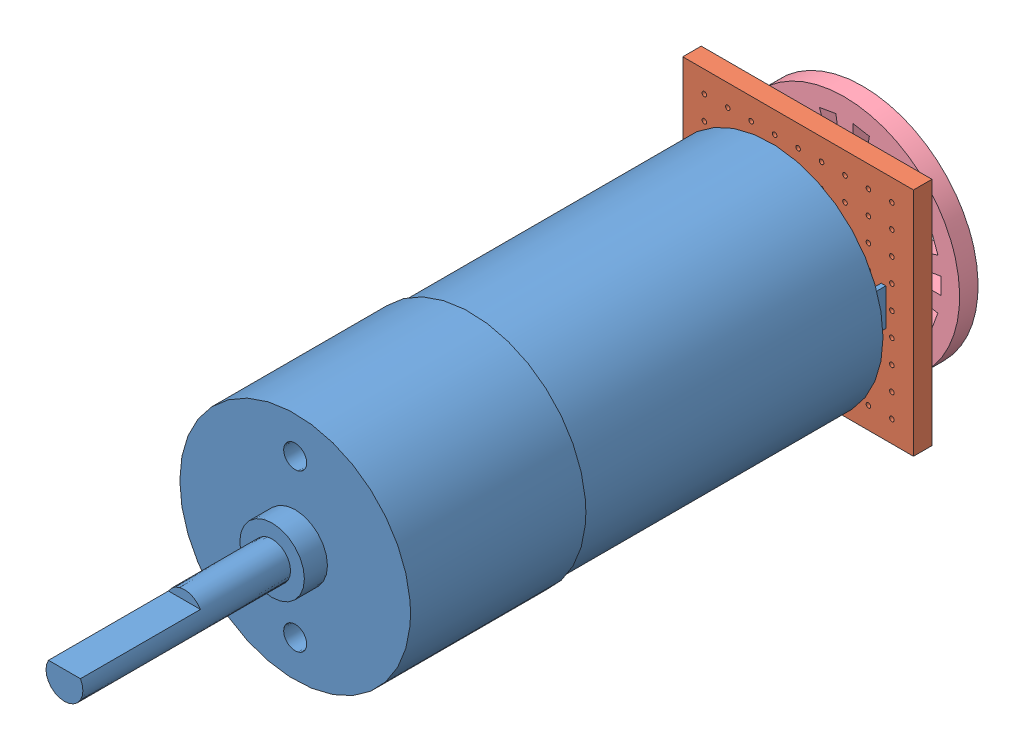
SolidWorks assembly motor_asm, configuration Default. Lengths in mm.
Overall size (31.79 31.79 86.5).
5 component instances, 4 part files, 11 mates.
Components (placement in the parent):
- DCMOTOR25 6v 325rpm-1: DCMOTOR25 6v 325rpm [Default] at (25.2687 40.3416 68.9723) size (25 25 84.5)
- encoder_pcb-1: encoder_pcb [Default] at (25.2687 40.3416 31.4723) x (1 0 0) z (0 -1 0) size (25 2 25)
- qre1113gr-1: qre1113gr [Default] at (25.2187 49.2416 31.4723) x (1 0 0) z (0 1 0) size (4.8 1.7 3.6)
- qre1113gr-3: qre1113gr [Default] at (19.1522 34.2958 31.4723) x (-0.707107 0.707107 0) z (-0.707107 -0.707107 0) size (4.8 1.7 3.6)
- encoder_disk-1: encoder_disk [Default] at (25.2687 40.3416 28.4723) x (0.326622 -0.945155 0) z (0.945155 0.326622 0) size (25 5 25)
Mates (geometry in assembly coordinates):
- 일치1: coincident anti-aligned: plane of DCMOTOR25 6v 325rpm-1 through (25.2687 40.3416 33.4723) normal (0 0 -1); plane of encoder_pcb-1 through (25.2687 40.3416 33.4723) normal (0 0 1)
- 동심1: concentric aligned: cylinder of DCMOTOR25 6v 325rpm-1 through (25.2687 40.3416 28.4723) axis (0 0 1) radius 1; cylinder of encoder_pcb-1 through (25.2687 40.3416 31.4723) axis (0 0 1) radius 1.2
- 평행1: parallel aligned: plane of DCMOTOR25 6v 325rpm-1 through (34.2687 42.3416 30.9723) normal (0 1 0); plane of encoder_pcb-1 through (12.7687 52.8416 33.4723) normal (0 1 0)
- 일치3: coincident anti-aligned: plane of encoder_pcb-1 through (25.2687 40.3416 31.4723) normal (0 0 -1); plane of qre1113gr-1 through (25.2187 49.2416 31.4723) normal (0 0 1)
- 거리2: distance = 10.7 mm aligned: line of assembly; plane of qre1113gr-1 through (23.7687 51.0416 29.7723) normal (0 1 0)
- 거리1: distance = 11.1 mm aligned: plane of encoder_pcb-1 through (37.7687 52.8416 33.4723) normal (1 0 0); plane of qre1113gr-1 through (26.6687 47.4416 29.7723) normal (1 0 0)
- 일치8: coincident anti-aligned: plane of encoder_pcb-1 through (25.2687 40.3416 31.4723) normal (0 0 -1); plane of qre1113gr-3 through (19.1522 34.2958 31.4723) normal (0 0 1)
- 거리6: distance = 10.4 mm: plane of qre1113gr-3 through (18.9047 31.9977 29.7723) normal (-0.707107 -0.707107 0); line of assembly
- 거리5: distance = 1.5 mm: line of assembly; plane of qre1113gr-3 through (19.3997 36.5939 29.7723) normal (-0.707107 0.707107 0)
- 거리7: distance = 5 mm aligned: plane of encoder_pcb-1 through (25.2687 40.3416 31.4723) normal (0 0 -1); plane of encoder_disk-1 through (25.2687 40.3416 26.4723) normal (0 0 -1)
- 동심2: concentric anti-aligned: cylinder of DCMOTOR25 6v 325rpm-1 through (25.2687 40.3416 28.4723) axis (0 0 1) radius 1; cylinder of encoder_disk-1 through (25.2687 40.3416 48.4723) axis (0 0 -1) radius 1
